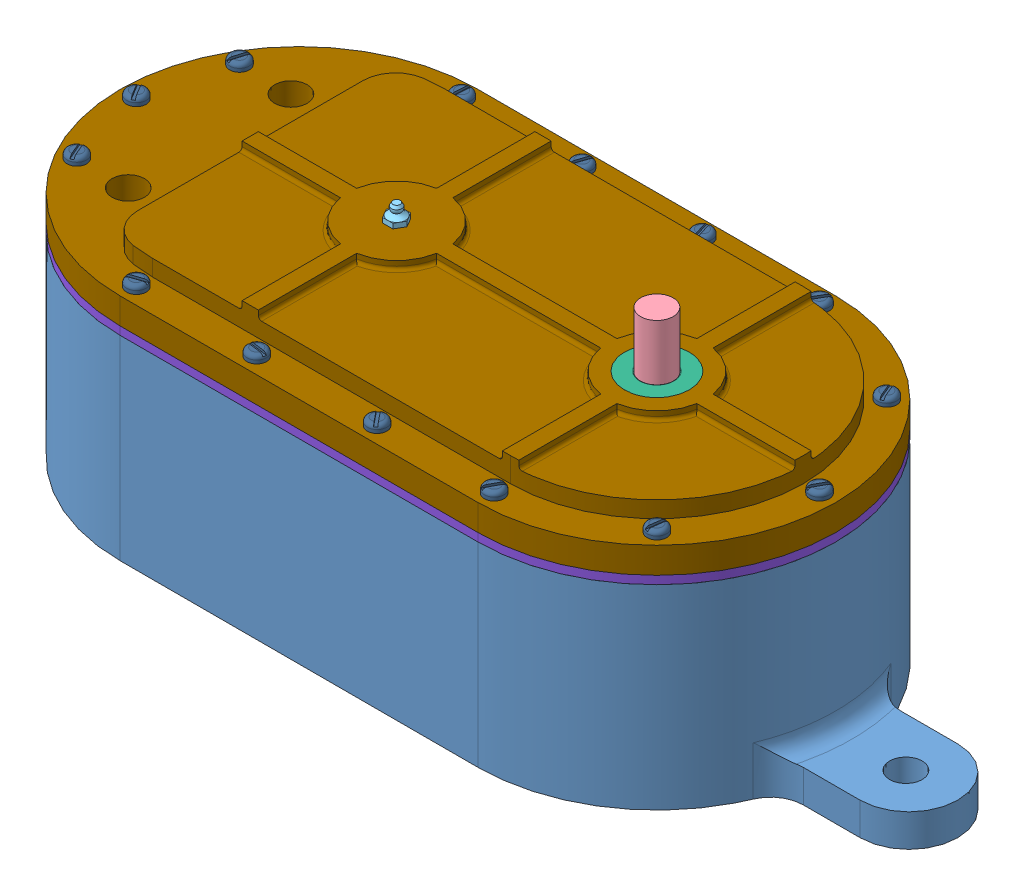
SolidWorks assembly FInal_WONG_P10-19, configuration Default. Lengths in mm.
Overall size (515 190 226.71).
29 component instances, 10 part files, 60 mates.
Components (placement in the parent):
- Casing-1: Casing [Default] at origin size (515 120 220)
- Shaft, Input-1: Shaft, Input [Default] at (0 75 0) x (1 0 0) z (0 1 0) size (25 25 75)
- Shaft, Neutral-1: Shaft, Neutral [Default] at (110 0 0) x (0.409136 0 0.912473) z (0 -1 0) size (30 30 115)
- Shaft, Output-1: Shaft, Output [Default] at (220 190 0) x (1 0 0) z (0 1 0) size (30 30 190)
- Lubrication nipple-1: Lubrication nipple [Default] at (60 151 0) size (13.16 14.8 12.3)
- thrust ball bearing2_68_am-1: thrust ball bearing2_68_am [AFBMA 24.1.5 - 20TA12 - 10,SI,NC,10_68] at (0 7 0) x (0 1 0) z (-0.32157 0 0.946886) size (14 40 40)
- thrust ball bearing2_68_am-2: thrust ball bearing2_68_am [AFBMA 24.1.5 - 20TA12 - 10,SI,NC,10_68] at (220 7 0) x (0 -1 0) z (0 0 1) size (14 40 40)
- thrust ball bearing2_68_am-3: thrust ball bearing2_68_am [AFBMA 24.1.5 - 20TA12 - 10,SI,NC,10_68] at (220 149 0) x (0 -1 0) z (0.924309 0 0.381644) size (14 40 40)
- thrust ball bearing2_68_am-4: thrust ball bearing2_68_am [AFBMA 24.1.5 - 20TA12 - 10,SI,NC,10_68] at (110 7 0) x (0 -1 0) z (0 0 1) size (14 40 40)
- spur gear_am-5: spur gear_am [Metric - Spur gear 2M 30T 20PA 20FW ---S30O75H40L25R1] at (110 94.9999 0) x (0 -1 0) z (-0.451232 0 -0.892406) size (40 63.76 64)
- spur gear_am-6: spur gear_am [Metric - Spur gear 2M 30T 20PA 20FW ---S30O75H40L25R1] at (0 54.9999 0) x (0 -1 0) z (-0.962435 0 -0.271514) size (40 63.76 64)
- spur gear_am-7: spur gear_am [Metric - Spur gear 2M 80T 20PA 20FW ---S80O75H40L30R1] at (220 94.9999 0) x (0 -1 0) z (0.977132 0 0.212635) size (40 163.92 163.92)
- spur gear_am-8: spur gear_am [Metric - Spur gear 2M 80T 20PA 20FW ---S80O75H40L30R1] at (110 54.9999 0) x (0 -1 0) z (-0.839112 0 0.543959) size (40 163.92 163.92)
- Gasket-2: Gasket [Default] at (0 120 0) size (440 5 220)
- CoverNew-1: CoverNew [Default] at (0 125 0) size (440 31 220)
- pan slot head_am-1: pan slot head_am [B18.6.7M - M6 x 1.0 x 35 Slotted PHMS --35N] at (290.7107 145.6 -70.7107) x (0 -1 0) z (-0.386834 0 -0.922149) size (39.6 12 12)
- pan slot head_am-2: pan slot head_am [B18.6.7M - M6 x 1.0 x 35 Slotted PHMS --35N] at (220 145.6 100) x (0 -1 0) z (-0.479618 0 0.877477) size (39.6 12 12)
- pan slot head_am-3: pan slot head_am [B18.6.7M - M6 x 1.0 x 35 Slotted PHMS --35N] at (220 145.6 -100) x (0 -1 0) z (-0.506038 0 0.862511) size (39.6 12 12)
- pan slot head_am-4: pan slot head_am [B18.6.7M - M6 x 1.0 x 35 Slotted PHMS --35N] at (290.7107 145.6 70.7107) x (0 -1 0) z (-0.136629 0 0.990622) size (39.6 12 12)
- pan slot head_am-5: pan slot head_am [B18.6.7M - M6 x 1.0 x 35 Slotted PHMS --35N] at (148 145.6 -100) x (0 -1 0) z (-0.294556 0 -0.955634) size (39.6 12 12)
- pan slot head_am-6: pan slot head_am [B18.6.7M - M6 x 1.0 x 35 Slotted PHMS --35N] at (148 145.6 100) x (0 -1 0) z (0.630002 0 0.776594) size (39.6 12 12)
- pan slot head_am-7: pan slot head_am [B18.6.7M - M6 x 1.0 x 35 Slotted PHMS --35N] at (0 145.6 100) x (0 -1 0) z (-0.947028 0 0.321152) size (39.6 12 12)
- pan slot head_am-8: pan slot head_am [B18.6.7M - M6 x 1.0 x 35 Slotted PHMS --35N] at (-86.6025 145.6 -50) x (0 -1 0) z (-0.290996 0 0.956724) size (39.6 12 12)
- pan slot head_am-9: pan slot head_am [B18.6.7M - M6 x 1.0 x 35 Slotted PHMS --35N] at (74 145.6 100) x (0 -1 0) z (-0.990798 0 -0.13535) size (39.6 12 12)
- pan slot head_am-10: pan slot head_am [B18.6.7M - M6 x 1.0 x 35 Slotted PHMS --35N] at (320 145.6 0) x (0 -1 0) z (0.47977 0 -0.877394) size (39.6 12 12)
- pan slot head_am-13: pan slot head_am [B18.6.7M - M6 x 1.0 x 35 Slotted PHMS --35N] at (74 145.6 -100) x (0 -1 0) z (-0.318353 0 0.947972) size (39.6 12 12)
- pan slot head_am-14: pan slot head_am [B18.6.7M - M6 x 1.0 x 35 Slotted PHMS --35N] at (0 145.6 -100) x (0 -1 0) z (-0.065062 0 0.997881) size (39.6 12 12)
- pan slot head_am-15: pan slot head_am [B18.6.7M - M6 x 1.0 x 35 Slotted PHMS --35N] at (-86.6025 145.6 50) x (0 -1 0) z (0.399509 0 0.916729) size (39.6 12 12)
- pan slot head_am-16: pan slot head_am [B18.6.7M - M6 x 1.0 x 35 Slotted PHMS --35N] at (-100 145.6 0) x (0 -1 0) z (0.51887 0 0.854853) size (39.6 12 12)
Mates (geometry in assembly coordinates):
- Concentric2: concentric aligned: cylinder of Casing-1 through (0 0 0) axis (0 1 0) radius 20; cylinder of thrust ball bearing2_68_am-1 through (0 -27.925 0) axis (0 1 0) radius 20
- Coincident3: coincident aligned: plane of Casing-1 through (340 0 50) normal (0 -1 0); plane of thrust ball bearing2_68_am-1 through (-9.4689 0 -3.2157) normal (0 -1 0)
- Concentric3: concentric anti-aligned: cylinder of Shaft, Input-1 through (0 0 0) axis (0 1 0) radius 10.02; cylinder of thrust ball bearing2_68_am-1 through (0 41.925 0) axis (0 -1 0) radius 10
- Concentric4: concentric anti-aligned: cylinder of Casing-1 through (110 0 0) axis (0 1 0) radius 20; cylinder of thrust ball bearing2_68_am-4 through (110 41.925 0) axis (0 -1 0) radius 20
- Coincident4: coincident aligned: plane of Casing-1 through (340 0 50) normal (0 -1 0); plane of thrust ball bearing2_68_am-4 through (120 0 0) normal (0 -1 0)
- Concentric5: concentric anti-aligned: cylinder of Casing-1 through (220 0 0) axis (0 1 0) radius 20; cylinder of thrust ball bearing2_68_am-2 through (220 41.925 0) axis (0 -1 0) radius 20
- Coincident5: coincident aligned: plane of Casing-1 through (340 0 50) normal (0 -1 0); circle of thrust ball bearing2_68_am-2
- Concentric7: concentric anti-aligned: cylinder of Shaft, Neutral-1 through (110 35 0) axis (0 -1 0) radius 10.01; circle of thrust ball bearing2_68_am-4
- Coincident8: coincident aligned: plane of Casing-1 through (340 0 50) normal (0 -1 0); plane of Shaft, Input-1 through (0 0 0) normal (0 -1 0)
- Coincident9: coincident aligned: plane of Casing-1 through (340 0 50) normal (0 -1 0); plane of Shaft, Neutral-1 through (110 0 0) normal (0 -1 0)
- Concentric9: concentric anti-aligned: cylinder of Shaft, Output-1 through (220 0 0) axis (0 1 0) radius 10.01; cylinder of thrust ball bearing2_68_am-2 through (220 41.925 0) axis (0 -1 0) radius 10
- Coincident10: coincident aligned: plane of Casing-1 through (340 0 50) normal (0 -1 0); plane of Shaft, Output-1 through (220 0 0) normal (0 -1 0)
- Concentric10: concentric aligned: cylinder of Shaft, Input-1 through (0 35 0) axis (0 1 0) radius 12.5; cylinder of spur gear_am-6 through (0 14.9999 0) axis (0 1 0) radius 12.5
- Coincident11: coincident aligned: plane of Shaft, Input-1 through (0 75 0) normal (0 1 0); plane of spur gear_am-6 through (0 75 0) normal (0 1 0)
- Concentric11: concentric anti-aligned: cylinder of Shaft, Neutral-1 through (110 75 0) axis (0 -1 0) radius 15; cylinder of spur gear_am-8 through (110 14.9999 0) axis (0 1 0) radius 15
- Coincident12: coincident aligned: plane of Shaft, Neutral-1 through (110 75 0) normal (0 1 0); plane of spur gear_am-8 through (110 75 0) normal (0 1 0)
- Concentric12: concentric anti-aligned: cylinder of Shaft, Neutral-1 through (110 115 0) axis (0 -1 0) radius 12.5; cylinder of spur gear_am-5 through (110 54.9999 0) axis (0 1 0) radius 12.5
- Coincident13: coincident aligned: plane of Shaft, Neutral-1 through (110 115 0) normal (0 1 0); plane of spur gear_am-5 through (110 115 0) normal (0 1 0)
- Concentric13: concentric aligned: cylinder of Shaft, Output-1 through (220 35 0) axis (0 1 0) radius 15; cylinder of spur gear_am-7 through (220 54.9999 0) axis (0 1 0) radius 15
- Coincident14: coincident aligned: plane of Shaft, Output-1 through (220 115 0) normal (0 1 0); plane of spur gear_am-7 through (220 115 0) normal (0 1 0)
- Coincident16: coincident anti-aligned: plane of Casing-1 through (0 120 0) normal (0 1 0); plane of Gasket-2 through (0 120 0) normal (0 -1 0)
- Coincident17: coincident aligned: circle of Casing-1; circle of Gasket-2
- Coincident20: coincident aligned: plane of Casing-1 through (0 20 -110) normal (0 0 -1); plane of Gasket-2 through (0 125 -110) normal (0 0 -1)
- Concentric18: concentric anti-aligned: cylinder of thrust ball bearing2_68_am-3 through (220 183.925 0) axis (0 -1 0) radius 20; cylinder of CoverNew-1 through (220 125 0) axis (0 1 0) radius 20
- Coincident25: coincident aligned: plane of thrust ball bearing2_68_am-3 through (223.8164 156 -9.2431) normal (0 1 0); plane of CoverNew-1 through (0 156 0) normal (0 1 0)
- Concentric19: concentric aligned: cylinder of Shaft, Output-1 through (220 115 0) axis (0 1 0) radius 10.01; circle of thrust ball bearing2_68_am-3
- Coincident26: coincident aligned: circle of Gasket-2; circle of CoverNew-1
- Concentric21: concentric anti-aligned: cylinder of Lubrication nipple-1 through (60 156 0) axis (0 -1 0) radius 5; cylinder of CoverNew-1 through (60 156 0) axis (0 1 0) radius 4.25
- Coincident27: coincident anti-aligned: plane of Lubrication nipple-1 through (60 156 0) normal (0 -1 0); plane of CoverNew-1 through (0 156 0) normal (0 1 0)
- GearMate1: gear = 60 : 160 mm: circle of spur gear_am-8; circle of spur gear_am-6
- GearMate2: gear = 160 : 60 mm: circle of spur gear_am-5; circle of spur gear_am-8
- GearMate4: gear = 160 : 60 mm: circle of spur gear_am-5; circle of spur gear_am-7
- Concentric24: concentric aligned: cylinder of CoverNew-1 through (-100 141 0) axis (0 1 0) radius 3.4; cylinder of pan slot head_am-16 through (-100 171 0) axis (0 1 0) radius 3
- Coincident28: coincident anti-aligned: plane of CoverNew-1 through (0 141 0) normal (0 1 0); plane of pan slot head_am-16 through (-97.4354 141 -1.5566) normal (0 -1 0)
- Concentric38: concentric aligned: cylinder of CoverNew-1 through (-86.6025 141 -50) axis (0 1 0) radius 3.4; cylinder of pan slot head_am-8 through (-86.6025 171 -50) axis (0 1 0) radius 3
- Coincident31: coincident anti-aligned: plane of CoverNew-1 through (0 141 0) normal (0 1 0); plane of pan slot head_am-8 through (-83.7324 141 -49.127) normal (0 -1 0)
- Concentric39: concentric aligned: cylinder of CoverNew-1 through (0 141 -100) axis (0 1 0) radius 3.4; cylinder of pan slot head_am-14 through (0 171 -100) axis (0 1 0) radius 3
- Coincident32: coincident anti-aligned: plane of CoverNew-1 through (0 141 0) normal (0 1 0); plane of pan slot head_am-14 through (2.9936 141 -99.8048) normal (0 -1 0)
- Concentric40: concentric aligned: cylinder of CoverNew-1 through (74 141 -100) axis (0 1 0) radius 3.4; cylinder of pan slot head_am-13 through (74 171 -100) axis (0 1 0) radius 3
- Coincident33: coincident anti-aligned: plane of CoverNew-1 through (0 141 0) normal (0 1 0); plane of pan slot head_am-13 through (76.8439 141 -99.0449) normal (0 -1 0)
- Concentric41: concentric aligned: cylinder of CoverNew-1 through (148 141 -100) axis (0 1 0) radius 3.4; cylinder of pan slot head_am-5 through (148 171 -100) axis (0 1 0) radius 3
- Coincident34: coincident anti-aligned: plane of CoverNew-1 through (0 141 0) normal (0 1 0); plane of pan slot head_am-5 through (145.1331 141 -99.1163) normal (0 -1 0)
- Concentric42: concentric aligned: cylinder of CoverNew-1 through (220 141 -100) axis (0 1 0) radius 3.4; cylinder of pan slot head_am-3 through (220 171 -100) axis (0 1 0) radius 3
- Coincident35: coincident anti-aligned: plane of CoverNew-1 through (0 141 0) normal (0 1 0); plane of pan slot head_am-3 through (222.5875 141 -98.4819) normal (0 -1 0)
- Concentric43: concentric aligned: cylinder of CoverNew-1 through (-86.6025 141 50) axis (0 1 0) radius 3.4; cylinder of pan slot head_am-15 through (-86.6025 171 50) axis (0 1 0) radius 3
- Coincident36: coincident anti-aligned: plane of CoverNew-1 through (0 141 0) normal (0 1 0); plane of pan slot head_am-15 through (-83.8524 141 48.8015) normal (0 -1 0)
- Concentric44: concentric aligned: cylinder of CoverNew-1 through (0 141 100) axis (0 1 0) radius 3.4; cylinder of pan slot head_am-7 through (0 171 100) axis (0 1 0) radius 3
- Coincident37: coincident anti-aligned: plane of CoverNew-1 through (0 141 0) normal (0 1 0); plane of pan slot head_am-7 through (0.9635 141 102.8411) normal (0 -1 0)
- Concentric45: concentric aligned: cylinder of CoverNew-1 through (74 141 100) axis (0 1 0) radius 3.4; cylinder of pan slot head_am-9 through (74 171 100) axis (0 1 0) radius 3
- Coincident38: coincident anti-aligned: plane of CoverNew-1 through (0 141 0) normal (0 1 0); plane of pan slot head_am-9 through (73.594 141 102.9724) normal (0 -1 0)
- Concentric46: concentric aligned: cylinder of CoverNew-1 through (148 141 100) axis (0 1 0) radius 3.4; cylinder of pan slot head_am-6 through (148 171 100) axis (0 1 0) radius 3
- Coincident39: coincident anti-aligned: plane of CoverNew-1 through (0 141 0) normal (0 1 0); plane of pan slot head_am-6 through (150.3298 141 98.11) normal (0 -1 0)
- Concentric47: concentric aligned: cylinder of CoverNew-1 through (220 141 100) axis (0 1 0) radius 3.4; cylinder of pan slot head_am-2 through (220 171 100) axis (0 1 0) radius 3
- Coincident40: coincident anti-aligned: plane of CoverNew-1 through (0 141 0) normal (0 1 0); plane of pan slot head_am-2 through (222.6324 141 101.4389) normal (0 -1 0)
- Concentric48: concentric aligned: cylinder of CoverNew-1 through (290.7107 141 70.7107) axis (0 1 0) radius 3.4; cylinder of pan slot head_am-4 through (290.7107 171 70.7107) axis (0 1 0) radius 3
- Coincident41: coincident anti-aligned: plane of CoverNew-1 through (0 141 0) normal (0 1 0); plane of pan slot head_am-4 through (293.6825 141 71.1206) normal (0 -1 0)
- Concentric49: concentric aligned: cylinder of CoverNew-1 through (320 141 0) axis (0 1 0) radius 3.4; cylinder of pan slot head_am-10 through (320 171 0) axis (0 1 0) radius 3
- Coincident42: coincident anti-aligned: plane of CoverNew-1 through (0 141 0) normal (0 1 0); plane of pan slot head_am-10 through (317.3678 141 -1.4393) normal (0 -1 0)
- Concentric50: concentric aligned: cylinder of CoverNew-1 through (290.7107 141 -70.7107) axis (0 1 0) radius 3.4; cylinder of pan slot head_am-1 through (290.7107 171 -70.7107) axis (0 1 0) radius 3
- Coincident43: coincident anti-aligned: plane of CoverNew-1 through (0 141 0) normal (0 1 0); plane of pan slot head_am-1 through (287.9442 141 -69.5502) normal (0 -1 0)
